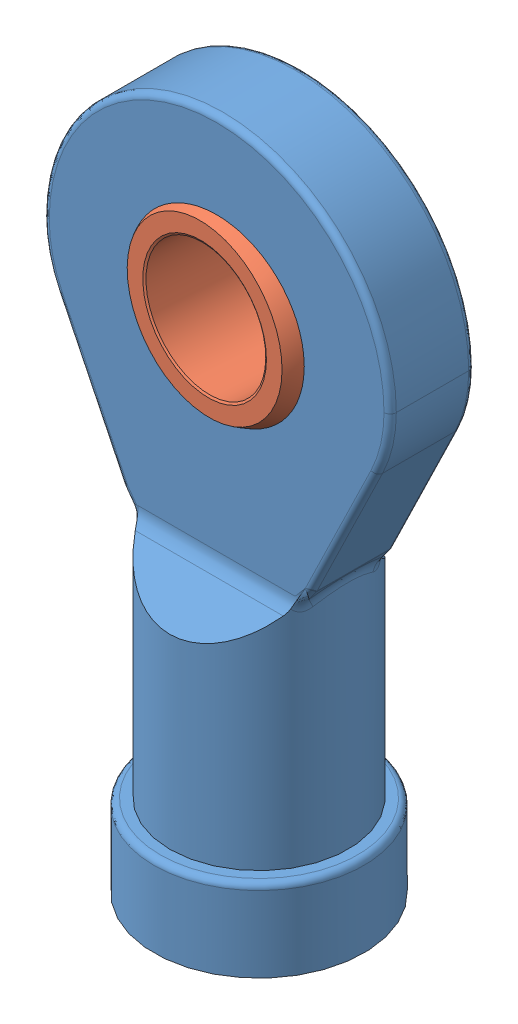
SolidWorks assembly igubal Spherical Rod End, configuration Default. Lengths in mm.
Overall size (43 86 25.98).
2 component instances, 2 part files, 1 mates.
Components (placement in the parent):
- igubal Spherical Rod End_Rod End-1: igubal Spherical Rod End_Rod End [Default] at (36.3685 5.5292 61.283) size (43 86 25.98)
- igubal Spherical Rod End_Ball-1: igubal Spherical Rod End_Ball [Default] at (36.3685 70.0299 61.283) x (0.997961 -0.010235 0.063004) z (-0.062993 0.0014 0.998013) size (24.13 24.13 12.7)
Mates (geometry in assembly coordinates):
- Concentric1: concentric: sphere of igubal Spherical Rod End_Rod End-1; sphere of igubal Spherical Rod End_Ball-1
